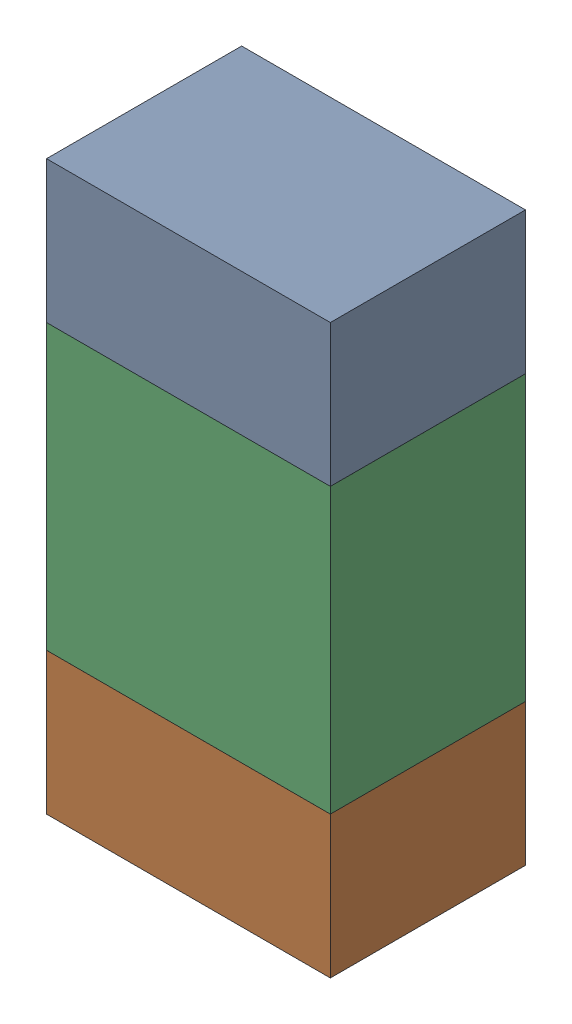
SolidWorks assembly R16, configuration ﾃﾞﾌｫﾙﾄ. Lengths in mm.
Overall size (0.8 1.6 0.55).
6 component instances, 2 part files, 0 mates.
Components (placement in the parent):
- 689261784-1: 689261784 [ﾃﾞﾌｫﾙﾄ] at (64.7501 49.5999 0) size (0.8 0.4 0.55)
  - Extruded_34-1: Extruded_34 [ﾃﾞﾌｫﾙﾄ] at origin size (0.8 0.4 0.55)
- 689261784-2: 689261784 [ﾃﾞﾌｫﾙﾄ] at (64.7501 48.3999 0) size (0.8 0.4 0.55)
  - Extruded_34-1: Extruded_34 [ﾃﾞﾌｫﾙﾄ] at origin size (0.8 0.4 0.55)
- 689261648-1: 689261648 [ﾃﾞﾌｫﾙﾄ] at (64.7501 49 0) size (0.8 0.8 0.55)
  - Extruded_33-1: Extruded_33 [ﾃﾞﾌｫﾙﾄ] at origin size (0.8 0.8 0.55)
